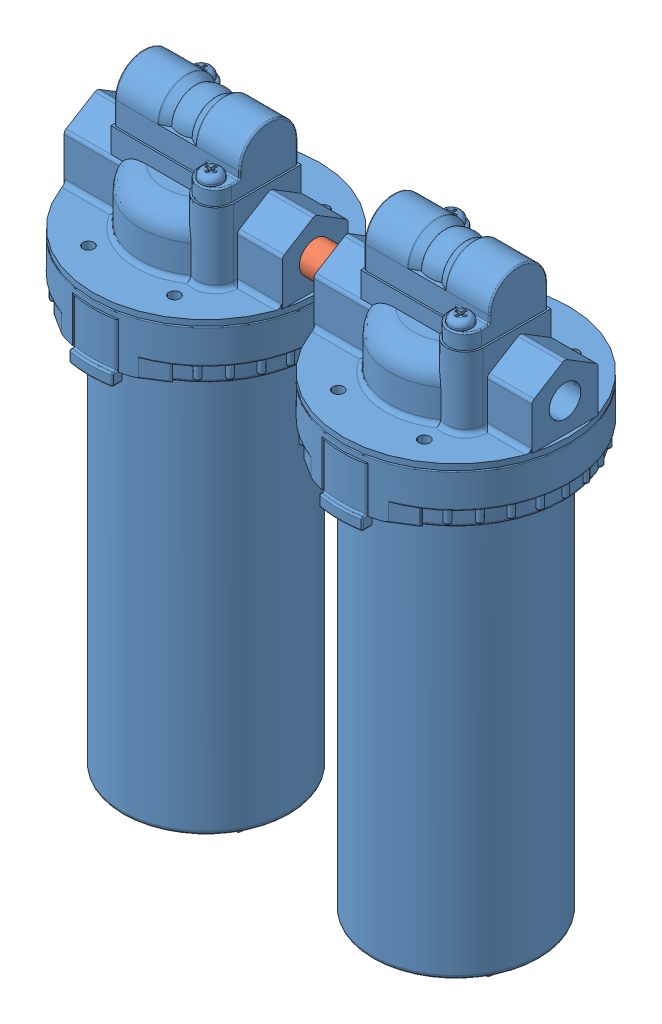
SolidWorks assembly ReadingTech_3P-060-M02-DCPi, configuration Default. Lengths in mm.
Overall size (206.63 271.65 99.95).
3 component instances, 2 part files, 3 mates.
Components (placement in the parent):
- ReadingTech_3P-060-M02-Pi-1: ReadingTech_3P-060-M02-Pi [Default] at (-49.8852 -114.9117 21.4068) size (98.17 271.65 99.95)
- ReadingTech_3P-060-M02-Pi-2: ReadingTech_3P-060-M02-Pi [Default] at (58.5728 -114.9117 21.4068) size (98.17 271.65 99.95)
- ReadingTech- 60cfm_connector_.25in-1: ReadingTech- 60cfm_connector_.25in [Default] at (11.2018 100.9883 21.4068) x (0 1 0) z (0 0 1) size (13.72 13.72 13.72)
Mates (geometry in assembly coordinates):
- Coincident1: coincident anti-aligned: circle of ReadingTech_3P-060-M02-Pi-1; circle of ReadingTech- 60cfm_connector_.25in-1
- Coincident2: coincident aligned: circle of ReadingTech_3P-060-M02-Pi-2; circle of ReadingTech- 60cfm_connector_.25in-1
- Coincident3: coincident aligned: plane of ReadingTech_3P-060-M02-Pi-1 through (-2.5142 88.2883 35.6943) normal (0 0 1); plane of ReadingTech_3P-060-M02-Pi-2 through (105.9438 88.2883 35.6943) normal (0 0 1)
